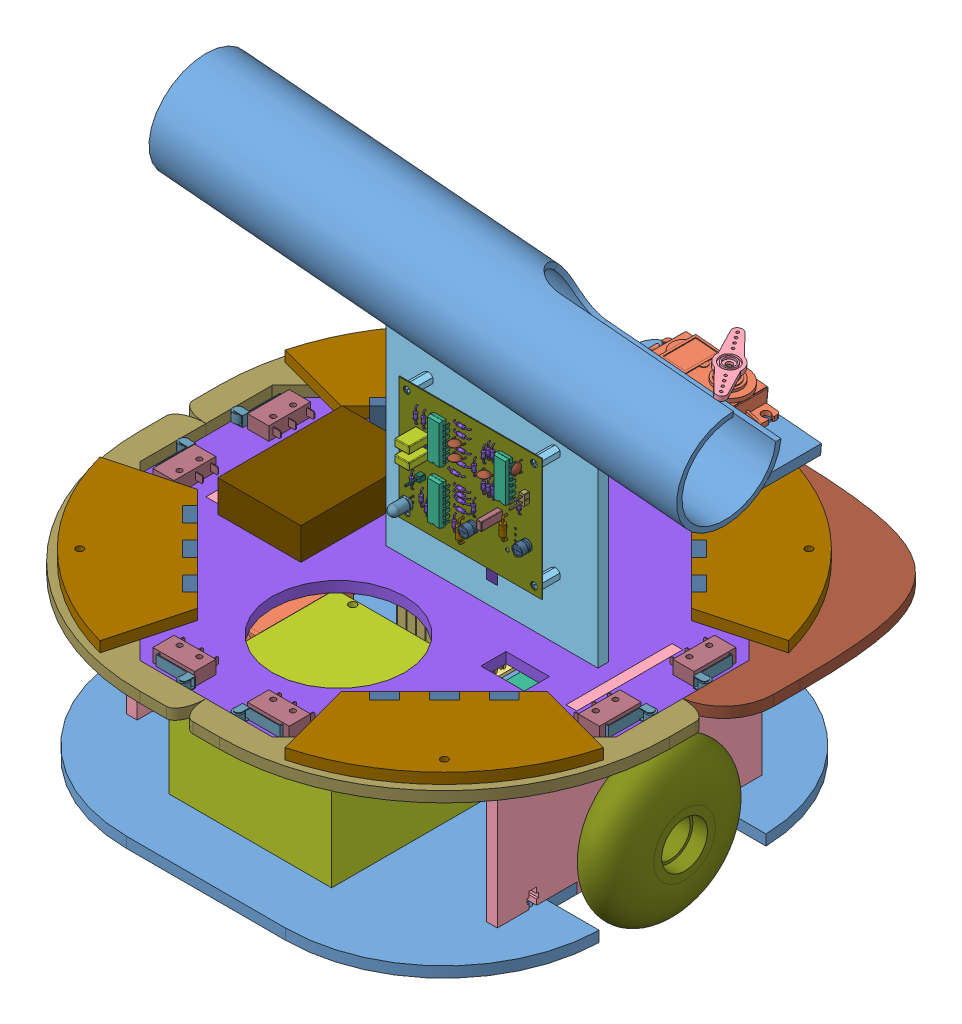
SolidWorks assembly robot, configuration Default. Lengths in mm.
Overall size (265.72 249.87 254.13).
161 component instances, 36 part files, 31 mates.
Components (placement in the parent):
- motorized_base-1: motorized_base [Default] at (19.7747 -28.0542 -6.7577) size (261.36 101.28 254.13)
  - layer0-1: layer0 [Default] at (-111.8693 8.5971 124.8526) size (228.55 5.08 228.6)
  - dc_motor-2: dc_motor [Default] at (-56.1893 13.6771 41.5526) x (0 1 0) z (0 0 1) size (32 41.21 78.8)
  - L298N Motor Driver-1: L298N Motor Driver [Default] at (-23.2077 23.6771 -25.3618) size (43.5 26 43.5)
  - motor_mount-2: motor_mount [Default] at (-86.4693 8.5971 74.0526) x (0 0 -1) z (1 0 0) size (127 76.2 5.08)
  - 94868A166_Female Threaded Hex Standoff-1: 94868A166_Female Threaded Hex Standoff [94868A166] at (-41.9577 18.6771 -6.6118) x (1 0 0) z (0 1 0) size (4.5 5.2 10.38)
  - 94868A166_Female Threaded Hex Standoff-2: 94868A166_Female Threaded Hex Standoff [94868A166] at (-4.4577 18.6771 -6.6118) x (-0.837169 0 -0.546944) z (0 -1 0) size (4.5 5.2 10.38)
  - 94868A166_Female Threaded Hex Standoff-3: 94868A166_Female Threaded Hex Standoff [94868A166] at (-41.9577 18.6771 -44.1118) x (1 0 0) z (0 -1 0) size (4.5 5.2 10.38)
  - 94868A166_Female Threaded Hex Standoff-4: 94868A166_Female Threaded Hex Standoff [94868A166] at (-4.4577 18.6771 -44.1118) x (1 0 0) z (0 -1 0) size (4.5 5.2 10.38)
  - battery-1: battery [Default] at (16.594 13.6771 -93.4489) x (0 0 1) z (-1 0 0) size (107 26 30)
  - uno32_stack-1: uno32_stack [Default] at (-43.0727 13.6771 97.1064) size (78 45 80)
  - layer1-1: layer1 [Default] at (-111.8693 79.7171 124.8526) size (228.6 5.08 228.6)
  - bumper_total_RL-7: bumper_total_RL [MirrorDefault] at (71.7591 20.1998 -64.3503) size (134.33 15.24 127.03)
    - bumper_top-1: bumper_top [MirrorDefault] at (-52.8514 69.6772 58.426) size (86.19 5.08 86.19)
    - bumper_flange-1: bumper_flange [MirrorDefault] at (-24.4456 59.5172 -5.9008) x (0.707107 0 0.707107) z (-0.707107 0 0.707107) size (50.8 15.24 5.08)
    - bumper_RL-2: bumper_RL [Default] at (-62.9783 64.5972 68.5529) size (134.33 5.14 127.03)
  - bumper_total-3: bumper_total [MirrorDefault] at (-72.4722 20.1998 -58.7757) x (0 0 -1) z (1 0 0) size (127.1 15.24 127.1)
    - bumper_top-1: bumper_top [MirrorDefault] at (-52.8514 69.6772 58.426) size (86.19 5.08 86.19)
    - bumper_flange-1: bumper_flange [MirrorDefault] at (-24.4456 59.5172 -5.9008) x (0.707107 0 0.707107) z (-0.707107 0 0.707107) size (50.8 15.24 5.08)
    - bumper-2: bumper [Default] at (-62.9783 64.5972 68.5529) size (127.1 5.21 127.1)
  - bumper_total-4: bumper_total [MirrorDefault] at (-66.8976 20.1998 85.4555) x (-1 0 0) z (0 0 -1) size (127.1 15.24 127.1)
    - bumper_top-1: bumper_top [MirrorDefault] at (-52.8514 69.6772 58.426) size (86.19 5.08 86.19)
    - bumper_flange-1: bumper_flange [MirrorDefault] at (-24.4456 59.5172 -5.9008) x (0.707107 0 0.707107) z (-0.707107 0 0.707107) size (50.8 15.24 5.08)
    - bumper-2: bumper [Default] at (-62.9783 64.5972 68.5529) size (127.1 5.21 127.1)
  - bumper_total-5: bumper_total [MirrorDefault] at (77.3336 20.1998 79.8809) x (0 0 1) z (-1 0 0) size (127.1 15.24 127.1)
    - bumper_top-1: bumper_top [MirrorDefault] at (-52.8514 69.6772 58.426) size (86.19 5.08 86.19)
    - bumper_flange-1: bumper_flange [MirrorDefault] at (-24.4456 59.5172 -5.9008) x (0.707107 0 0.707107) z (-0.707107 0 0.707107) size (50.8 15.24 5.08)
    - bumper-2: bumper [Default] at (-62.9783 64.5972 68.5529) size (127.1 5.21 127.1)
  - switch-1: switch [Default] at (-98.756 96.4594 48.0833) x (0 0 1) z (0 -1 0) size (22.05 20.9 6.4)
    - switch_body-1: switch_body [Default] at (-24.8307 -4.2868 5.2624) size (20 13.7 6.4)
    - switch_lever-1: switch_lever [Default] at (-7.8307 2.3132 5.9624) x (-1 0 0) z (0 0 -1) size (19.05 10.8 5)
  - switch-2: switch [Default] at (-98.756 79.5347 -26.9781) x (0 0 -1) z (0 1 0) size (22.05 20.9 6.4)
    - switch_body-1: switch_body [Default] at (-24.8307 -4.2868 5.2624) size (20 13.7 6.4)
    - switch_lever-1: switch_lever [Default] at (-7.8307 2.3132 5.9624) x (-1 0 0) z (0 0 -1) size (19.05 10.8 5)
  - wheel_spacer_plastic-1: wheel_spacer_plastic [Default] at (-91.0093 29.6771 10.5526) size (14.48 21.97 21.97)
  - switch-9: switch [Default] at (103.6175 79.5347 48.0833) x (0 0 1) z (0 1 0) size (22.05 20.9 6.4)
    - switch_body-1: switch_body [Default] at (-24.8307 -4.2868 5.2624) size (20 13.7 6.4)
    - switch_lever-1: switch_lever [Default] at (-7.8307 2.3132 5.9624) x (-1 0 0) z (0 0 -1) size (19.05 10.8 5)
  - switch-10: switch [Default] at (103.6175 96.4594 -26.9781) x (0 0 -1) z (0 -1 0) size (22.05 20.9 6.4)
    - switch_body-1: switch_body [Default] at (-24.8307 -4.2868 5.2624) size (20 13.7 6.4)
    - switch_lever-1: switch_lever [Default] at (-7.8307 2.3132 5.9624) x (-1 0 0) z (0 0 -1) size (19.05 10.8 5)
  - switch-11: switch [Default] at (39.9614 96.4594 111.7394) x (1 0 0) z (0 -1 0) size (22.05 20.9 6.4)
    - switch_body-1: switch_body [Default] at (-24.8307 -4.2868 5.2624) size (20 13.7 6.4)
    - switch_lever-1: switch_lever [Default] at (-7.8307 2.3132 5.9624) x (-1 0 0) z (0 0 -1) size (19.05 10.8 5)
  - switch-12: switch [Default] at (-35.0999 79.5347 111.7394) x (-1 0 0) z (0 1 0) size (22.05 20.9 6.4)
    - switch_body-1: switch_body [Default] at (-24.8307 -4.2868 5.2624) size (20 13.7 6.4)
    - switch_lever-1: switch_lever [Default] at (-7.8307 2.3132 5.9624) x (-1 0 0) z (0 0 -1) size (19.05 10.8 5)
  - switch-13: switch [Default] at (39.9614 79.5347 -90.6342) x (1 0 0) z (0 1 0) size (22.05 20.9 6.4)
    - switch_body-1: switch_body [Default] at (-24.8307 -4.2868 5.2624) size (20 13.7 6.4)
    - switch_lever-1: switch_lever [Default] at (-7.8307 2.3132 5.9624) x (-1 0 0) z (0 0 -1) size (19.05 10.8 5)
  - switch-14: switch [Default] at (-35.0999 96.4594 -90.6342) x (-1 0 0) z (0 -1 0) size (22.05 20.9 6.4)
    - switch_body-1: switch_body [Default] at (-24.8307 -4.2868 5.2624) size (20 13.7 6.4)
    - switch_lever-1: switch_lever [Default] at (-7.8307 2.3132 5.9624) x (-1 0 0) z (0 0 -1) size (19.05 10.8 5)
  - dc_motor-4: dc_motor [Default] at (61.0507 13.6771 -20.4474) x (0 1 0) z (0 0 -1) size (32 41.21 78.8)
  - motor_mount-5: motor_mount [Default] at (91.3307 8.5971 -52.9474) x (0 0 1) z (-1 0 0) size (127 76.2 5.08)
  - wheel_spacer_plastic-3: wheel_spacer_plastic [Default] at (93.3927 29.6771 10.5526) x (-1 0 0) z (0 0 -1) size (14.48 21.97 21.97)
  - skate_wheel_72mm-3: skate_wheel_72mm [Default] at (93.2507 29.6771 10.5526) size (24.4 72 72)
  - skate_wheel_72mm-4: skate_wheel_72mm [Default] at (-115.2673 29.6771 10.5526) size (24.4 72 72)
- Tape_Sensor-1: Tape_Sensor [Default] at origin size (10 6.4 5.7)
- TrackWire-1: TrackWire [Default] at (-36.6809 56.7428 3.7949) size (39.88 15.24 59.69)
- launcher-1: launcher [Default] at (72.8901 159.3273 14.5606) x (0 0 -1) z (0.996195 -0.087156 0) size (79.25 65.91 254)
  - ramp-1: ramp [Default] at (10.7657 16.5495 84.6757) size (70.54 50.04 254)
  - MG996R SBORKA-1: MG996R SBORKA [Default] at (83.2673 -35.9401 64.2412) x (0 0 -1) z (0 1 0) size (54.5 37.92 47)
    - Servo MG996R-1: Servo MG996R [По умолчанию] at (25.4655 37.2326 19.0996) size (54.5 20.5 40.7)
    - Servo MG996R Shaft-1: Servo MG996R Shaft [Default] at (15.2655 37.2326 51.2996) x (0.766243 -0.642551 0) z (-0.642551 -0.766243 0) size (6 9 6)
    - Servo MG996R arm01-1: Servo MG996R arm01 [Default] at (15.2655 37.2326 58.5996) x (0.579489 -0.81498 0) z (0 0 -1) size (38 12 5.5)
- tower_support-1: tower_support [Default] at (98.4054 51.6628 6.3349) x (0 0 -1) z (1 0 0) size (5.08 105.95 101.6)
- beacondetector-v2-1: beacondetector-v2 [Default] at (192.9188 11.1244 16.3349) x (-1 0 0) z (0 0 1) size (68.58 58.42 14.9)
  - beacondetector-v2.step-1: beacondetector-v2.step [Default] at origin size (68.58 58.42 14.9)
    - DIP-14_W7.62mm.step-1: DIP-14_W7.62mm.step [Default] at (155.4834 -81.1734 0.45) size (7.87 19.05 6.98)
      - SOLID.step-1: SOLID.step [Default] at origin size (7.87 19.05 6.98)
    - C_Rect_L7.0mm_W3.5mm_P5.00mm.step-1: C_Rect_L7.0mm_W3.5mm_P5.00mm.step [Default] at (170.7134 -110.9234 0.45) x (-1 0 0) z (0 0 1) size (7 3.5 11.9)
      - SOLID-0.step-1: SOLID-0.step [Default] at origin size (7 3.5 11.9)
    - R_Axial_DIN0204_L3.6mm_D1.6mm_P7.62mm_Horizontal.step-1: R_Axial_DIN0204_L3.6mm_D1.6mm_P7.62mm_Horizontal.step [Default] at (166.9134 -121.8634 0.45) x (0 1 0) z (0 0 1) size (8.12 1.6 4.72)
      - SOLID-1.step-1: SOLID-1.step [Default] at origin size (8.12 1.6 4.72)
    - R_Axial_DIN0204_L3.6mm_D1.6mm_P7.62mm_Horizontal.step-2: R_Axial_DIN0204_L3.6mm_D1.6mm_P7.62mm_Horizontal.step [Default] at (145.2234 -95.7984 0.45) size (8.12 1.6 4.72)
      - SOLID-1.step-1: SOLID-1.step [Default] at origin size (8.12 1.6 4.72)
    - D_DO-41_SOD81_P10.16mm_Horizontal.step-1: D_DO-41_SOD81_P10.16mm_Horizontal.step [Default] at (127.8656 -97.897 0.45) x (0 1 0) z (0 0 1) size (10.96 3.14 5.71)
      - SOLID-2.step-1: SOLID-2.step [Default] at origin size (10.96 3.14 5.71)
    - R_Axial_DIN0204_L3.6mm_D1.6mm_P7.62mm_Horizontal.step-3: R_Axial_DIN0204_L3.6mm_D1.6mm_P7.62mm_Horizontal.step [Default] at (145.2034 -89.5984 0.45) size (8.12 1.6 4.72)
      - SOLID-1.step-1: SOLID-1.step [Default] at origin size (8.12 1.6 4.72)
    - R_Axial_DIN0204_L3.6mm_D1.6mm_P7.62mm_Horizontal.step-4: R_Axial_DIN0204_L3.6mm_D1.6mm_P7.62mm_Horizontal.step [Default] at (135.9334 -124.3134 0.45) x (0 1 0) z (0 0 1) size (8.12 1.6 4.72)
      - SOLID-1.step-1: SOLID-1.step [Default] at origin size (8.12 1.6 4.72)
    - R_Axial_DIN0204_L3.6mm_D1.6mm_P7.62mm_Horizontal.step-5: R_Axial_DIN0204_L3.6mm_D1.6mm_P7.62mm_Horizontal.step [Default] at (135.9334 -101.3534 0.45) x (0 -1 0) z (0 0 1) size (8.12 1.6 4.72)
      - SOLID-1.step-1: SOLID-1.step [Default] at origin size (8.12 1.6 4.72)
    - CP_Radial_D5.0mm_P2.50mm.step-1: CP_Radial_D5.0mm_P2.50mm.step [Default] at (143.8434 -86.2984 0.45) x (0 1 0) z (0 0 1) size (6.82 7.94 7)
      - SOLID-3.step-1: SOLID-3.step [Default] at origin size (6.82 7.94 7)
    - R_Axial_DIN0204_L3.6mm_D1.6mm_P7.62mm_Horizontal.step-6: R_Axial_DIN0204_L3.6mm_D1.6mm_P7.62mm_Horizontal.step [Default] at (133.6334 -108.9734 0.45) x (0 1 0) z (0 0 1) size (8.12 1.6 4.72)
      - SOLID-1.step-1: SOLID-1.step [Default] at origin size (8.12 1.6 4.72)
    - R_Axial_DIN0204_L3.6mm_D1.6mm_P7.62mm_Horizontal.step-7: R_Axial_DIN0204_L3.6mm_D1.6mm_P7.62mm_Horizontal.step [Default] at (145.1102 -120.8024 0.45) size (8.12 1.6 4.72)
      - SOLID-1.step-1: SOLID-1.step [Default] at origin size (8.12 1.6 4.72)
    - R_Axial_DIN0204_L3.6mm_D1.6mm_P7.62mm_Horizontal.step-8: R_Axial_DIN0204_L3.6mm_D1.6mm_P7.62mm_Horizontal.step [Default] at (142.6834 -114.2334 0.45) x (0 1 0) z (0 0 1) size (8.12 1.6 4.72)
      - SOLID-1.step-1: SOLID-1.step [Default] at origin size (8.12 1.6 4.72)
    - R_Axial_DIN0204_L3.6mm_D1.6mm_P7.62mm_Horizontal.step-9: R_Axial_DIN0204_L3.6mm_D1.6mm_P7.62mm_Horizontal.step [Default] at (152.8234 -93.4484 0.45) x (-1 0 0) z (0 0 1) size (8.12 1.6 4.72)
      - SOLID-1.step-1: SOLID-1.step [Default] at origin size (8.12 1.6 4.72)
    - R_Axial_DIN0204_L3.6mm_D1.6mm_P7.62mm_Horizontal.step-10: R_Axial_DIN0204_L3.6mm_D1.6mm_P7.62mm_Horizontal.step [Default] at (147.8788 -103.7336 0.45) size (8.12 1.6 4.72)
      - SOLID-1.step-1: SOLID-1.step [Default] at origin size (8.12 1.6 4.72)
    - C_Disc_D5.0mm_W2.5mm_P5.00mm.step-1: C_Disc_D5.0mm_W2.5mm_P5.00mm.step [Default] at (138.6334 -111.6734 0.45) x (-1 0 0) z (0 0 1) size (5.58 2.5 7.49)
      - SOLID-4.step-1: SOLID-4.step [Default] at origin size (5.58 2.5 7.49)
    - R_Axial_DIN0204_L3.6mm_D1.6mm_P7.62mm_Horizontal.step-11: R_Axial_DIN0204_L3.6mm_D1.6mm_P7.62mm_Horizontal.step [Default] at (165.4834 -78.5884 0.45) x (0 -1 0) z (0 0 1) size (8.12 1.6 4.72)
      - SOLID-1.step-1: SOLID-1.step [Default] at origin size (8.12 1.6 4.72)
    - CP_Radial_D5.0mm_P2.50mm.step-2: CP_Radial_D5.0mm_P2.50mm.step [Default] at (117.9656 -91.607 0.45) x (0 1 0) z (0 0 1) size (6.82 7.94 7)
      - SOLID-3.step-1: SOLID-3.step [Default] at origin size (6.82 7.94 7)
    - DIP-14_W7.62mm.step-2: DIP-14_W7.62mm.step [Default] at (155.4834 -106.5734 0.45) size (7.87 19.05 6.98)
      - SOLID.step-1: SOLID.step [Default] at origin size (7.87 19.05 6.98)
    - R_Axial_DIN0204_L3.6mm_D1.6mm_P7.62mm_Horizontal.step-12: R_Axial_DIN0204_L3.6mm_D1.6mm_P7.62mm_Horizontal.step [Default] at (152.7302 -114.5032 0.45) x (-1 0 0) z (0 0 1) size (8.12 1.6 4.72)
      - SOLID-1.step-1: SOLID-1.step [Default] at origin size (8.12 1.6 4.72)
    - R_Axial_DIN0204_L3.6mm_D1.6mm_P7.62mm_Horizontal.step-13: R_Axial_DIN0204_L3.6mm_D1.6mm_P7.62mm_Horizontal.step [Default] at (152.8434 -98.4984 0.45) x (-1 0 0) z (0 0 1) size (8.12 1.6 4.72)
      - SOLID-1.step-1: SOLID-1.step [Default] at origin size (8.12 1.6 4.72)
    - R_Axial_DIN0204_L3.6mm_D1.6mm_P7.62mm_Horizontal.step-14: R_Axial_DIN0204_L3.6mm_D1.6mm_P7.62mm_Horizontal.step [Default] at (172.6692 -86.2584 0.45) x (0 -1 0) z (0 0 1) size (8.12 1.6 4.72)
      - SOLID-1.step-1: SOLID-1.step [Default] at origin size (8.12 1.6 4.72)
    - R_Axial_DIN0204_L3.6mm_D1.6mm_P7.62mm_Horizontal.step-15: R_Axial_DIN0204_L3.6mm_D1.6mm_P7.62mm_Horizontal.step [Default] at (165.6334 -107.4634 0.45) size (8.12 1.6 4.72)
      - SOLID-1.step-1: SOLID-1.step [Default] at origin size (8.12 1.6 4.72)
    - C_Disc_D5.0mm_W2.5mm_P5.00mm.step-2: C_Disc_D5.0mm_W2.5mm_P5.00mm.step [Default] at (147.5834 -111.6234 0.45) size (5.58 2.5 7.49)
      - SOLID-4.step-1: SOLID-4.step [Default] at origin size (5.58 2.5 7.49)
    - PinHeader_1x02_P2.54mm_Vertical.step-1: PinHeader_1x02_P2.54mm_Vertical.step [Default] at (118.1334 -109.0734 0.45) size (2.54 5.08 11.54)
      - SOLID-5.step-1: SOLID-5.step [Default] at origin size (2.54 5.08 11.54)
    - R_Axial_DIN0204_L3.6mm_D1.6mm_P7.62mm_Horizontal.step-16: R_Axial_DIN0204_L3.6mm_D1.6mm_P7.62mm_Horizontal.step [Default] at (133.8334 -116.7134 0.45) x (0 -1 0) z (0 0 1) size (8.12 1.6 4.72)
      - SOLID-1.step-1: SOLID-1.step [Default] at origin size (8.12 1.6 4.72)
    - C_Disc_D5.0mm_W2.5mm_P5.00mm.step-3: C_Disc_D5.0mm_W2.5mm_P5.00mm.step [Default] at (120.6334 -119.2734 0.45) x (0 -1 0) z (0 0 1) size (5.58 2.5 7.49)
      - SOLID-4.step-1: SOLID-4.step [Default] at origin size (5.58 2.5 7.49)
    - R_Axial_DIN0204_L3.6mm_D1.6mm_P7.62mm_Horizontal.step-17: R_Axial_DIN0204_L3.6mm_D1.6mm_P7.62mm_Horizontal.step [Default] at (145.1102 -124.6632 0.45) size (8.12 1.6 4.72)
      - SOLID-1.step-1: SOLID-1.step [Default] at origin size (8.12 1.6 4.72)
    - DIP-14_W7.62mm.step-3: DIP-14_W7.62mm.step [Default] at (123.7334 -106.5734 0.45) size (7.87 19.05 6.98)
      - SOLID.step-1: SOLID.step [Default] at origin size (7.87 19.05 6.98)
    - R_Axial_DIN0204_L3.6mm_D1.6mm_P7.62mm_Horizontal.step-18: R_Axial_DIN0204_L3.6mm_D1.6mm_P7.62mm_Horizontal.step [Default] at (152.2434 -86.2484 0.45) x (0 1 0) z (0 0 1) size (8.12 1.6 4.72)
      - SOLID-1.step-1: SOLID-1.step [Default] at origin size (8.12 1.6 4.72)
    - C_Rect_L4.0mm_W2.5mm_P2.50mm.step-1: C_Rect_L4.0mm_W2.5mm_P2.50mm.step [Default] at (131.1656 -97.897 0.45) x (0 1 0) z (0 0 1) size (4 2.5 11.9)
      - SOLID-6.step-1: SOLID-6.step [Default] at origin size (4 2.5 11.9)
    - R_Axial_DIN0204_L3.6mm_D1.6mm_P7.62mm_Horizontal.step-19: R_Axial_DIN0204_L3.6mm_D1.6mm_P7.62mm_Horizontal.step [Default] at (121.1334 -109.0734 0.45) x (0 1 0) z (0 0 1) size (8.12 1.6 4.72)
      - SOLID-1.step-1: SOLID-1.step [Default] at origin size (8.12 1.6 4.72)
    - LED_D5.0mm.step-1: LED_D5.0mm.step [Default] at (172.6946 -83.1342 0.45) x (0 1 0) z (0 0 1) size (5.4 6.76 14.1)
      - SOLID-7.step-1: SOLID-7.step [Default] at origin size (5.4 6.76 14.1)
    - R_Axial_DIN0204_L3.6mm_D1.6mm_P7.62mm_Horizontal.step-20: R_Axial_DIN0204_L3.6mm_D1.6mm_P7.62mm_Horizontal.step [Default] at (142.9434 -89.5984 0.45) x (0 -1 0) z (0 0 1) size (8.12 1.6 4.72)
      - SOLID-1.step-1: SOLID-1.step [Default] at origin size (8.12 1.6 4.72)
    - C_Disc_D5.0mm_W2.5mm_P5.00mm.step-4: C_Disc_D5.0mm_W2.5mm_P5.00mm.step [Default] at (147.7302 -117.5512 0.45) size (5.58 2.5 7.49)
      - SOLID-4.step-1: SOLID-4.step [Default] at origin size (5.58 2.5 7.49)
    - R_Axial_DIN0204_L3.6mm_D1.6mm_P7.62mm_Horizontal.step-21: R_Axial_DIN0204_L3.6mm_D1.6mm_P7.62mm_Horizontal.step [Default] at (138.1334 -114.1934 0.45) x (0 -1 0) z (0 0 1) size (8.12 1.6 4.72)
      - SOLID-1.step-1: SOLID-1.step [Default] at origin size (8.12 1.6 4.72)
    - C_Rect_L7.0mm_W3.5mm_P5.00mm.step-2: C_Rect_L7.0mm_W3.5mm_P5.00mm.step [Default] at (170.7134 -104.1634 0.45) x (-1 0 0) z (0 0 1) size (7 3.5 11.9)
      - SOLID-0.step-1: SOLID-0.step [Default] at origin size (7 3.5 11.9)
    - R_Axial_DIN0204_L3.6mm_D1.6mm_P7.62mm_Horizontal.step-22: R_Axial_DIN0204_L3.6mm_D1.6mm_P7.62mm_Horizontal.step [Default] at (138.2334 -108.9734 0.45) x (0 1 0) z (0 0 1) size (8.12 1.6 4.72)
      - SOLID-1.step-1: SOLID-1.step [Default] at origin size (8.12 1.6 4.72)
    - R_Axial_DIN0204_L3.6mm_D1.6mm_P7.62mm_Horizontal.step-23: R_Axial_DIN0204_L3.6mm_D1.6mm_P7.62mm_Horizontal.step [Default] at (152.5934 -108.9234 0.45) x (-1 0 0) z (0 0 1) size (8.12 1.6 4.72)
      - SOLID-1.step-1: SOLID-1.step [Default] at origin size (8.12 1.6 4.72)
    - R_Axial_DIN0204_L3.6mm_D1.6mm_P7.62mm_Horizontal.step-24: R_Axial_DIN0204_L3.6mm_D1.6mm_P7.62mm_Horizontal.step [Default] at (168.0434 -81.1784 0.45) x (0 -1 0) z (0 0 1) size (8.12 1.6 4.72)
      - SOLID-1.step-1: SOLID-1.step [Default] at origin size (8.12 1.6 4.72)
    - R_Axial_DIN0204_L3.6mm_D1.6mm_P7.62mm_Horizontal.step-25: R_Axial_DIN0204_L3.6mm_D1.6mm_P7.62mm_Horizontal.step [Default] at (170.7134 -114.2434 0.45) x (0 -1 0) z (0 0 1) size (8.12 1.6 4.72)
      - SOLID-1.step-1: SOLID-1.step [Default] at origin size (8.12 1.6 4.72)
    - D_DO-41_SOD81_P10.16mm_Horizontal.step-2: D_DO-41_SOD81_P10.16mm_Horizontal.step [Default] at (148.7434 -86.2684 0.45) x (0 1 0) z (0 0 1) size (10.96 3.14 5.71)
      - SOLID-2.step-1: SOLID-2.step [Default] at origin size (10.96 3.14 5.71)
    - PinHeader_1x01_P2.54mm_Vertical.step-1: PinHeader_1x01_P2.54mm_Vertical.step [Default] at (168.1434 -93.8984 0.45) size (2.54 2.54 11.54)
      - SOLID-8.step-1: SOLID-8.step [Default] at origin size (2.54 2.54 11.54)
    - beacondetector-v2 PCB.step-1: beacondetector-v2 PCB.step [Default] at origin size (68.58 58.42 0.4)
- 94868A166_Female Threaded Hex Standoff-1: 94868A166_Female Threaded Hex Standoff [94868A166] at (17.1254 85.9528 11.3349) size (4.5 5.2 10.38)
- 94868A166_Female Threaded Hex Standoff-2: 94868A166_Female Threaded Hex Standoff [94868A166] at (78.0854 136.7528 11.3349) size (4.5 5.2 10.38)
- 94868A166_Female Threaded Hex Standoff-3: 94868A166_Female Threaded Hex Standoff [94868A166] at (17.1254 136.7528 11.3349) size (4.5 5.2 10.38)
- 94868A166_Female Threaded Hex Standoff-4: 94868A166_Female Threaded Hex Standoff [94868A166] at (78.0854 85.9528 11.3349) size (4.5 5.2 10.38)
- tower_support_flange-1: tower_support_flange [Default] at (45.0654 51.6628 6.3349) x (0 0 -1) z (1 0 0) size (38.1 76.2 5.08)
- skeg-1: skeg [Default] at (24.7454 -12.7094 86.3449) x (-1 0 0) z (0 0 1) size (5.08 13.46 38.1)
- skeg-2: skeg [Default] at (24.7454 -12.7094 -78.7551) x (-1 0 0) z (0 0 1) size (5.08 13.46 38.1)
Mates (geometry in assembly coordinates):
- Coincident1: coincident: plane of motorized_base-1/layer1-1 through (-92.0946 56.7428 118.0949) normal (0 1 0); plane of TrackWire-1 through (-36.6809 56.7428 3.7949) normal (0 -1 0)
- Width1: width: plane of motorized_base-1/layer1-1 through (-92.0946 56.7428 -110.5051) normal (0 0 -1); plane of motorized_base-1/layer1-1 through (-92.0946 56.7428 118.0949) normal (0 0 1); plane of TrackWire-1 through (-56.6199 71.9828 33.6399) normal (0 0 1); plane of TrackWire-1 through (-56.6199 71.9828 -26.0501) normal (0 0 -1)
- Distance7: distance = 35.4747 mm: plane of TrackWire-1 through (-56.6199 71.9828 33.6399) normal (-1 0 0); plane of motorized_base-1/layer1-1 through (-92.0946 56.7428 118.0949) normal (-1 0 0)
- Tangent1: tangent: cylinder of launcher-1/ramp-1 through (-94.3475 190.5714 3.7949) axis (0.996195 -0.087156 0) radius 25.019; plane of assembly through (13.649 156.0083 0) normal (0.087156 0.996195 0)
- Parallel7: parallel: plane of launcher-1/ramp-1 through (157.1198 150.5322 -67.6271) normal (-0.087156 -0.996195 0); plane of assembly through (13.649 156.0083 0) normal (0.087156 0.996195 0)
- Parallel9: parallel: plane of launcher-1/MG996R SBORKA-1/Servo MG996R-1 through (132.2592 157.8066 -41.7241) normal (0 0 -1); plane of assembly through (0 0 0) normal (0 0 1)
- Width8: width: plane of motorized_base-1/layer1-1 through (-92.0946 56.7428 118.0949) normal (0 0 1); plane of motorized_base-1/layer1-1 through (-92.0946 56.7428 -110.5051) normal (0 0 -1); cylinder of launcher-1/ramp-1 through (-94.3475 190.5714 3.7949) axis (0.996195 -0.087156 0) radius 25.019
- Coincident19: coincident: plane of launcher-1/ramp-1 through (158.686 168.4338 3.7949) normal (0.996195 -0.087156 0); plane of assembly through (142.8564 -12.4983 0) normal (0.996195 -0.087156 0)
- Width9: width: plane of motorized_base-1/layer1-1 through (-92.0946 56.7428 118.0949) normal (0 0 1); plane of motorized_base-1/layer1-1 through (-92.0946 56.7428 -110.5051) normal (0 0 -1); plane of tower_support-1 through (98.4054 215.4961 1.2549) normal (0 0 -1); plane of tower_support-1 through (98.4054 215.4961 6.3349) normal (0 0 1)
- Distance8: distance = 38.1 mm: plane of tower_support-1 through (98.4054 215.4961 6.3349) normal (1 0 0); plane of motorized_base-1/layer1-1 through (136.5054 56.7428 118.0949) normal (1 0 0)
- Concentric1: concentric: circle of beacondetector-v2-1/beacondetector-v2.step-1/beacondetector-v2 PCB.step-1; circle of 94868A166_Female Threaded Hex Standoff-1
- Coincident20: coincident: plane of beacondetector-v2-1/beacondetector-v2.step-1/beacondetector-v2 PCB.step-1 through (47.6054 111.3528 16.3349) normal (0 0 -1); plane of 94868A166_Female Threaded Hex Standoff-1 through (17.1254 88.5509 16.3349) normal (0 0 1)
- Concentric2: concentric: circle of beacondetector-v2-1/beacondetector-v2.step-1/beacondetector-v2 PCB.step-1; circle of 94868A166_Female Threaded Hex Standoff-3
- Coincident21: coincident: plane of beacondetector-v2-1/beacondetector-v2.step-1/beacondetector-v2 PCB.step-1 through (47.6054 111.3528 16.3349) normal (0 0 -1); plane of 94868A166_Female Threaded Hex Standoff-3 through (17.1254 139.3509 16.3349) normal (0 0 1)
- Concentric3: concentric: circle of beacondetector-v2-1/beacondetector-v2.step-1/beacondetector-v2 PCB.step-1; circle of 94868A166_Female Threaded Hex Standoff-2
- Coincident22: coincident: plane of beacondetector-v2-1/beacondetector-v2.step-1/beacondetector-v2 PCB.step-1 through (47.6054 111.3528 16.3349) normal (0 0 -1); plane of 94868A166_Female Threaded Hex Standoff-2 through (78.0854 139.3509 16.3349) normal (0 0 1)
- Concentric4: concentric: circle of beacondetector-v2-1/beacondetector-v2.step-1/beacondetector-v2 PCB.step-1; circle of 94868A166_Female Threaded Hex Standoff-4
- Coincident24: coincident: plane of beacondetector-v2-1/beacondetector-v2.step-1/beacondetector-v2 PCB.step-1 through (47.6054 111.3528 16.3349) normal (0 0 -1); plane of 94868A166_Female Threaded Hex Standoff-4 through (78.0854 88.5509 16.3349) normal (0 0 1)
- Width10: width: plane of tower_support-1 through (98.4054 215.4961 6.3349) normal (1 0 0); plane of tower_support-1 through (-3.1946 215.4961 6.3349) normal (-1 0 0); plane of beacondetector-v2-1/beacondetector-v2.step-1/beacondetector-v2 PCB.step-1 through (13.3154 140.5628 16.3349) normal (-1 0 0); plane of beacondetector-v2-1/beacondetector-v2.step-1/beacondetector-v2 PCB.step-1 through (81.8954 82.1428 16.3349) normal (1 0 0)
- Distance9: distance = 25.4 mm: plane of motorized_base-1/layer1-1 through (-92.0946 56.7428 118.0949) normal (0 1 0); plane of beacondetector-v2-1/beacondetector-v2.step-1/beacondetector-v2 PCB.step-1 through (13.3154 82.1428 16.3349) normal (0 -1 0)
- Coincident26: coincident: plane of tower_support-1 through (98.4054 215.4961 6.3349) normal (0 0 1); plane of 94868A166_Female Threaded Hex Standoff-4 through (78.0854 88.5509 6.3349) normal (0 0 -1)
- Coincident27: coincident: plane of motorized_base-1/layer1-1 through (-92.0946 51.6628 118.0949) normal (0 -1 0); plane of tower_support-1 through (98.4054 51.6628 6.3349) normal (0 -1 0)
- Coincident28: coincident: plane of tower_support-1 through (98.4054 215.4961 1.2549) normal (0 0 -1); plane of tower_support_flange-1 through (45.0654 51.6628 1.2549) normal (0 0 1)
- Coincident29: coincident: plane of motorized_base-1/layer1-1 through (-92.0946 56.7428 118.0949) normal (0 1 0); plane of tower_support_flange-1 through (45.0654 56.7428 6.3349) normal (0 -1 0)
- Width11: width: plane of tower_support-1 through (-3.1946 215.4961 6.3349) normal (-1 0 0); plane of tower_support-1 through (98.4054 215.4961 6.3349) normal (1 0 0); plane of tower_support_flange-1 through (50.1454 51.6628 6.3349) normal (1 0 0); plane of tower_support_flange-1 through (45.0654 51.6628 6.3349) normal (-1 0 0)
- Width12: width: plane of motorized_base-1/layer0-1 through (-66.6946 -19.4582 -36.2051) normal (-1 0 0); plane of motorized_base-1/layer0-1 through (111.1054 -19.4582 -36.2051) normal (1 0 0); plane of skeg-2 through (24.7454 -12.7094 -78.7551) normal (1 0 0); plane of skeg-2 through (19.6654 -12.7094 -78.7551) normal (-1 0 0)
- Distance10: distance = 12.7 mm: line of skeg-2 through (19.6654 -19.4572 -97.8051) axis (1 0 0); plane of motorized_base-1/layer0-1 through (-92.0946 -14.3772 -110.5051) normal (0 0 -1)
- Distance11: distance = 12.7 mm: line of skeg-1 through (19.6654 -19.4572 105.3949) axis (1 0 0); plane of motorized_base-1/layer0-1 through (-92.0946 -14.3772 118.0949) normal (0 0 1)
- Coincident31: coincident: plane of motorized_base-1/layer0-1 through (-92.0946 -19.4572 118.0949) normal (0 -1 0); plane of skeg-1 through (19.6654 -19.4572 105.3949) normal (0 1 0)
- Width13: width: plane of motorized_base-1/layer0-1 through (-66.6946 -19.4582 -36.2051) normal (-1 0 0); plane of motorized_base-1/layer0-1 through (111.1054 -19.4582 -36.2051) normal (1 0 0); plane of skeg-1 through (24.7454 -12.7094 86.3449) normal (1 0 0); plane of skeg-1 through (19.6654 -12.7094 86.3449) normal (-1 0 0)
- Coincident32: coincident: plane of motorized_base-1/layer0-1 through (-92.0946 -19.4572 118.0949) normal (0 -1 0); plane of skeg-2 through (19.6654 -19.4572 -59.7051) normal (0 1 0)
